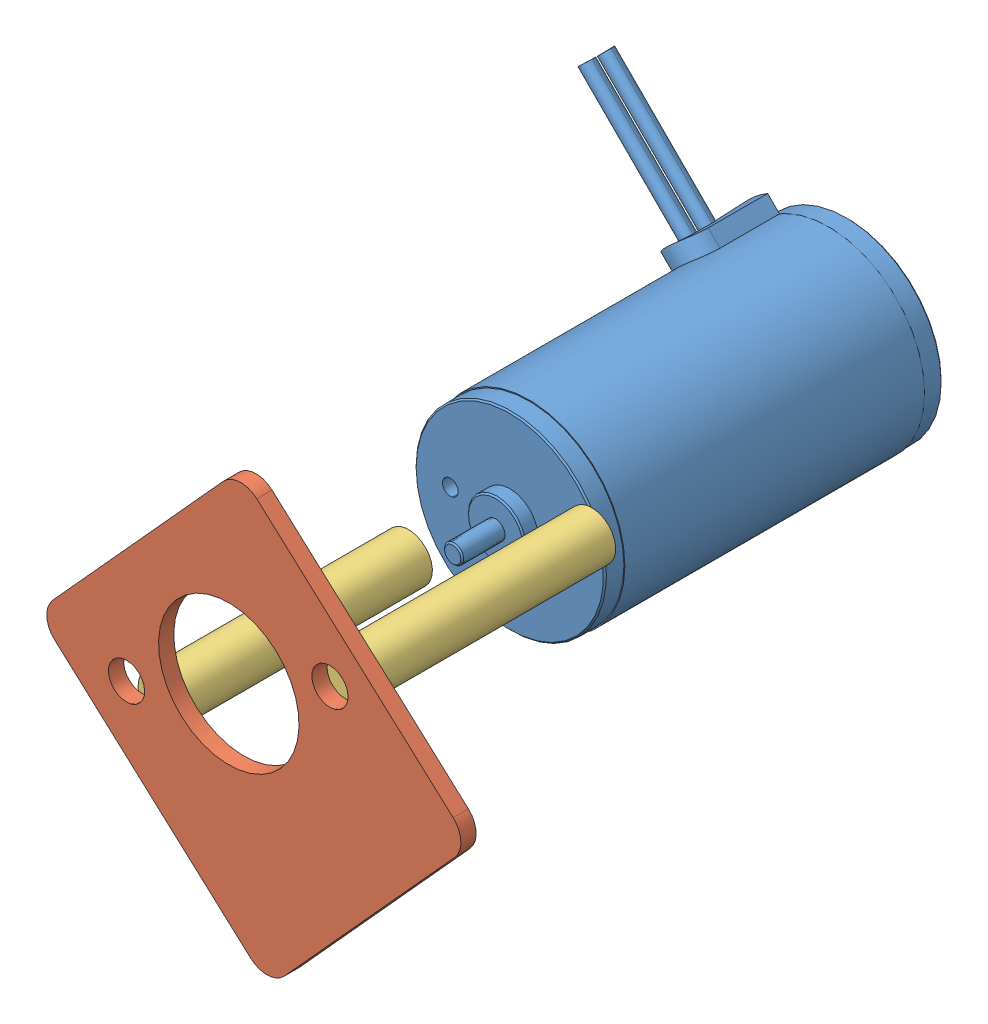
SolidWorks assembly motorCage, configuration Default. Lengths in mm.
Overall size (91.2 91.04 131.58).
3 component instances, 3 part files, 4 mates.
Components (placement in the parent):
- Bag CIM-1: Bag CIM [Default] at (30.1172 29.0362 104.6753) size (59.11 59.11 84.5)
- motorCagePlate-1: motorCagePlate [Default] at (35.3814 23.4975 160.5553) x (0.671439 0.741059 0) z (0.741059 -0.671439 0) size (63.32 3.2 65.7)
- motorCageSpacer-1: motorCageSpacer [Default] at (32.1109 27.5637 160.5553) x (0.856266 0.516535 0) z (-0.516535 0.856266 0) size (55 51.88 10)
Mates (geometry in assembly coordinates):
- Concentric1: concentric: cylinder of Bag CIM-1 through (30.1172 29.0362 116.6753) axis (0 0 -1) radius 2; cylinder of motorCagePlate-1 through (30.1172 29.0362 163.7553) axis (0 0 -1) radius 14.77
- Coincident1: coincident: plane of motorCagePlate-1 through (35.3814 23.4975 160.5553) normal (0 0 -1); plane of motorCageSpacer-1 through (12.8449 15.9416 160.5553) normal (0 0 1)
- Distance1: distance = 4 mm: plane of motorCageSpacer-1 through (12.8449 15.9416 108.6753) normal (0 0 -1); plane of Bag CIM-1 through (30.1172 29.0362 104.6753) normal (0 0 1)
- Concentric6: concentric: cylinder of motorCagePlate-1 through (51.3769 39.1857 163.7553) axis (0 0 -1) radius 3.81; cylinder of motorCageSpacer-1 through (51.3769 39.1857 108.6753) axis (0 0 1) radius 5
